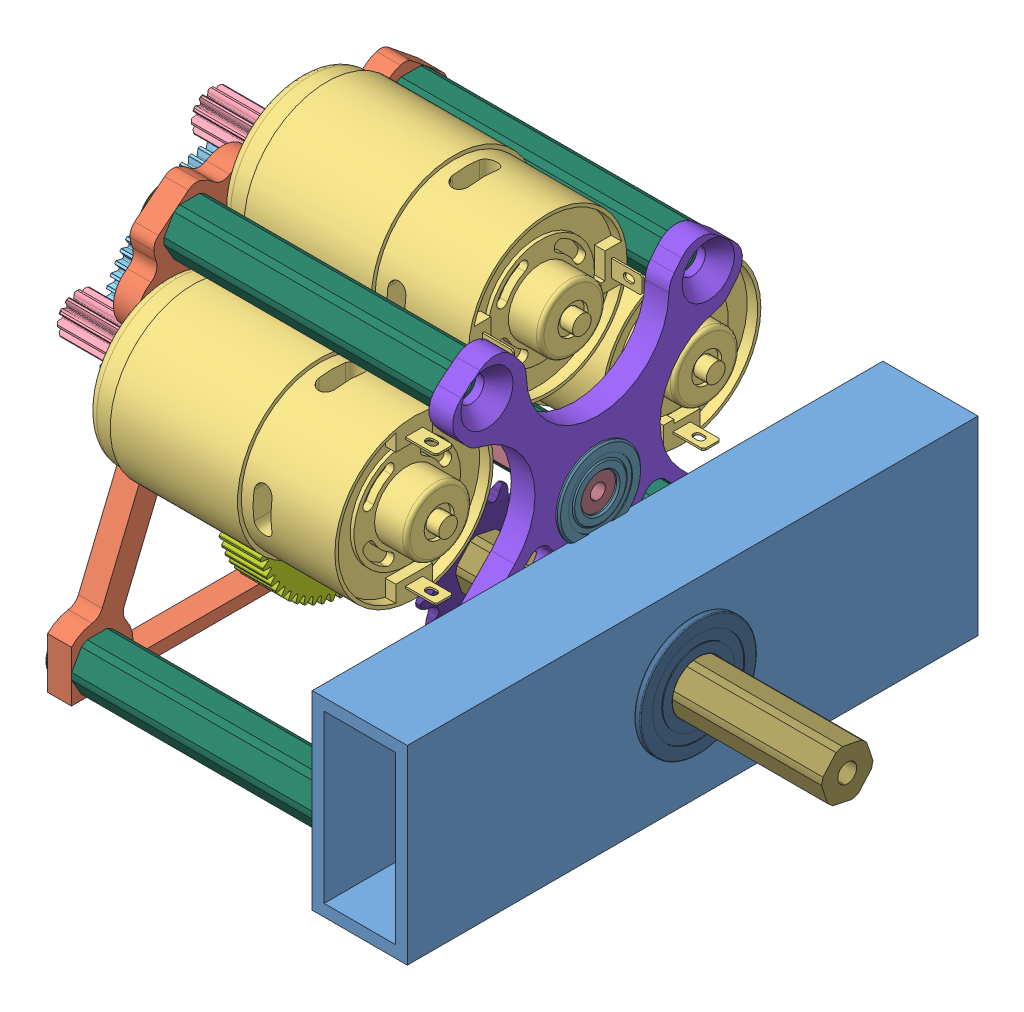
SolidWorks assembly Drivetrain Assembly, configuration Default. Lengths in mm.
Overall size (170.1 119.53 152.4).
29 component instances, 17 part files, 6 mates.
Components (placement in the parent):
- Drivetrain Box Tube-1: Drivetrain Box Tube [Default] at (50.1767 88.476 114.4435) size (25.4 50.8 152.4)
- Overall-1: Overall [Default] at (34.7378 41.2651 61.9044) x (0 0 1) z (-1 0 0) size (122.31 119.53 170.1)
  - Motor Plate-1: Motor Plate [Default] at (52.5392 48.7984 76.6361) size (122.27 104.47 6.35)
  - 775Pro-1: 775Pro [Default] at (16.8029 88.0373 76.6361) x (0 0 -1) z (-1 0 0) size (88 44.3 44.3)
  - 775Pro-2: 775Pro [Default] at (52.5392 117.0609 76.6361) x (0 0 -1) z (0 1 0) size (88 44.3 44.3)
  - 775Pro-3: 775Pro [Default] at (88.2754 88.0373 76.6361) x (0 0 -1) z (1 0 0) size (88 44.3 44.3)
  - WCP-0002 32DP 12T 775 Pinion-1: WCP-0002 32DP 12T 775 Pinion [Default] at (16.8029 88.0373 91.1611) x (0 0 1) z (-1 0 0) size (19.05 11.11 11.11)
  - WCP-0002 32DP 12T 775 Pinion-2: WCP-0002 32DP 12T 775 Pinion [Default] at (52.5392 117.0609 91.1611) x (0 0 1) z (-1 0 0) size (19.05 11.11 11.11)
  - WCP-0002 32DP 12T 775 Pinion-3: WCP-0002 32DP 12T 775 Pinion [Default] at (88.2754 88.0373 91.1611) x (0 0 1) z (-1 0 0) size (19.05 11.11 11.11)
  - WCP-0010 32DP 80T Gear-1: WCP-0010 32DP 80T Gear [Default] at (52.5392 80.5484 92.5365) x (0 0 -1) z (-0.294941 0.955516 0) size (12.65 65.09 65.09)
  - WCP-0005 20T 32DP Gear-1: WCP-0005 20T 32DP Gear [Default] at (52.5392 80.5484 68.2382) x (0 0 -1) z (0.974971 -0.222332 0) size (12.65 17.46 17.46)
  - WCP-0008 60T 32DP Gear-1: WCP-0008 60T 32DP Gear [Default] at (52.5392 48.7984 68.724) x (0 0 -1) z (0.978823 0.204708 0) size (12.65 49.21 49.21)
  - Output Plate-1: Output Plate [Default] at (52.5392 48.7984 -2.7389) size (122.27 103.88 6.35)
  - 217-2735 3_8 Hex Bearing-2: 217-2735 3_8 Hex Bearing [Default] at (52.5392 80.5484 82.9861) x (0.923728 0.383049 0) z (-0.383049 0.923728 0) size (31.12 7.94 31.12)
  - Thunderhex Bearing-2: Thunderhex Bearing [Default] at (52.5392 48.7984 1.2298) size (31.12 31.12 7.94)
  - 217-2731 1_2 Inch Bearing-1: 217-2731 1_2 Inch Bearing [Default] at (52.5392 48.7984 82.9861) x (1 0 0) z (0 1 0) size (31.12 7.94 31.12)
  - Output Shaft-1: Output Shaft [Default] at (52.5392 48.7984 -69.4139) x (0.312129 0.95004 0) z (0 0 1) size (13.75 12.7 152.4)
  - Internal Shaft-1: Internal Shaft [Default] at (52.4664 80.5259 -2.7389) x (-0.68003 -0.733184 0) z (0 0 1) size (11 9.53 101.6)
  - 6384K344_BALL BEARING-1: 6384K344_BALL BEARING [6384K344] at (52.5392 80.5484 0.8329) x (-0.923728 -0.383049 0) z (0 0 -1) size (25.4 25.4 10.32)
  - Gearbox Spacer-1: Gearbox Spacer [Default] at (22.9815 116.9422 3.6111) x (1 0 0) z (0 -1 0) size (13.75 73.03 12.7)
  - Gearbox Spacer-2: Gearbox Spacer [Default] at (-1.7391 28.6689 3.6111) x (1 0 0) z (0 -1 0) size (13.75 73.03 12.7)
  - Gearbox Spacer-3: Gearbox Spacer [Default] at (82.0968 116.9422 3.6111) x (1 0 0) z (0 -1 0) size (13.75 73.03 12.7)
  - Gearbox Spacer-4: Gearbox Spacer [Default] at (106.8174 28.6689 3.6111) x (1 0 0) z (0 -1 0) size (13.75 73.03 12.7)
  - 91253A537_ALLOY STEEL FLAT-HEAD SOCKET CAP SCREW-1: 91253A537_ALLOY STEEL FLAT-HEAD SOCKET CAP SCREW [91253A537] at (22.9815 116.9422 83.5412) size (13.49 13.49 25.8)
  - 91253A537_ALLOY STEEL FLAT-HEAD SOCKET CAP SCREW-2: 91253A537_ALLOY STEEL FLAT-HEAD SOCKET CAP SCREW [91253A537] at (82.0968 116.9422 83.5412) size (13.49 13.49 25.8)
  - 91253A537_ALLOY STEEL FLAT-HEAD SOCKET CAP SCREW-3: 91253A537_ALLOY STEEL FLAT-HEAD SOCKET CAP SCREW [91253A537] at (106.8174 28.6689 83.5412) size (13.49 13.49 25.8)
  - 91253A537_ALLOY STEEL FLAT-HEAD SOCKET CAP SCREW-4: 91253A537_ALLOY STEEL FLAT-HEAD SOCKET CAP SCREW [91253A537] at (-1.7391 28.6689 83.5412) size (13.49 13.49 25.8)
- Thunderhex Bearing-1: Thunderhex Bearing [Default] at (60.4955 90.0635 114.4435) x (0 0 -1) z (1 0 0) size (31.12 31.12 7.94)
- 2737T107_FINISHED-BORE SPROCKET FOR ANSI ROLLER CHAIN-1: 2737T107_FINISHED-BORE SPROCKET FOR ANSI ROLLER CHAIN [2737T107] at (5.0212 90.0635 114.4435) x (0 0.016499 0.999864) z (-1 0 0) size (31.06 31.63 12.7)
Mates (geometry in assembly coordinates):
- Coincident1: coincident aligned: plane of Drivetrain Box Tube-1 through (37.4767 63.076 190.6435) normal (0 -1 0); plane of Overall-1/Output Plate-1 through (31.1267 63.076 53.3073) normal (0 -1 0)
- Concentric1: concentric aligned: cylinder of Drivetrain Box Tube-1 through (37.4767 90.0635 114.4435) axis (1 0 0) radius 14.2875; cylinder of Overall-1/Output Shaft-1 through (-48.2483 90.0635 114.4435) axis (1 0 0) radius 6.875
- Coincident2: coincident anti-aligned: plane of Drivetrain Box Tube-1 through (37.4767 113.876 190.6435) normal (-1 0 0); plane of Overall-1/Output Plate-1 through (37.4767 129.3023 150.1798) normal (1 0 0)
- Coincident3: coincident anti-aligned: plane of Drivetrain Box Tube-1 through (62.8767 113.876 190.6435) normal (1 0 0); plane of Thunderhex Bearing-1 through (62.8767 104.351 114.4435) normal (-1 0 0)
- Concentric2: concentric aligned: cylinder of Overall-1/Output Shaft-1 through (-48.2483 90.0635 114.4435) axis (1 0 0) radius 6.875; cylinder of Thunderhex Bearing-1 through (113.7444 90.0635 114.4435) axis (1 0 0) radius 6.875
- Concentric3: concentric aligned: cylinder of Overall-1/Output Shaft-1 through (-48.2483 90.0635 114.4435) axis (1 0 0) radius 6.875; cylinder of 2737T107_FINISHED-BORE SPROCKET FOR ANSI ROLLER CHAIN-1 through (-6.2818 90.0635 114.4435) axis (1 0 0) radius 6.35
